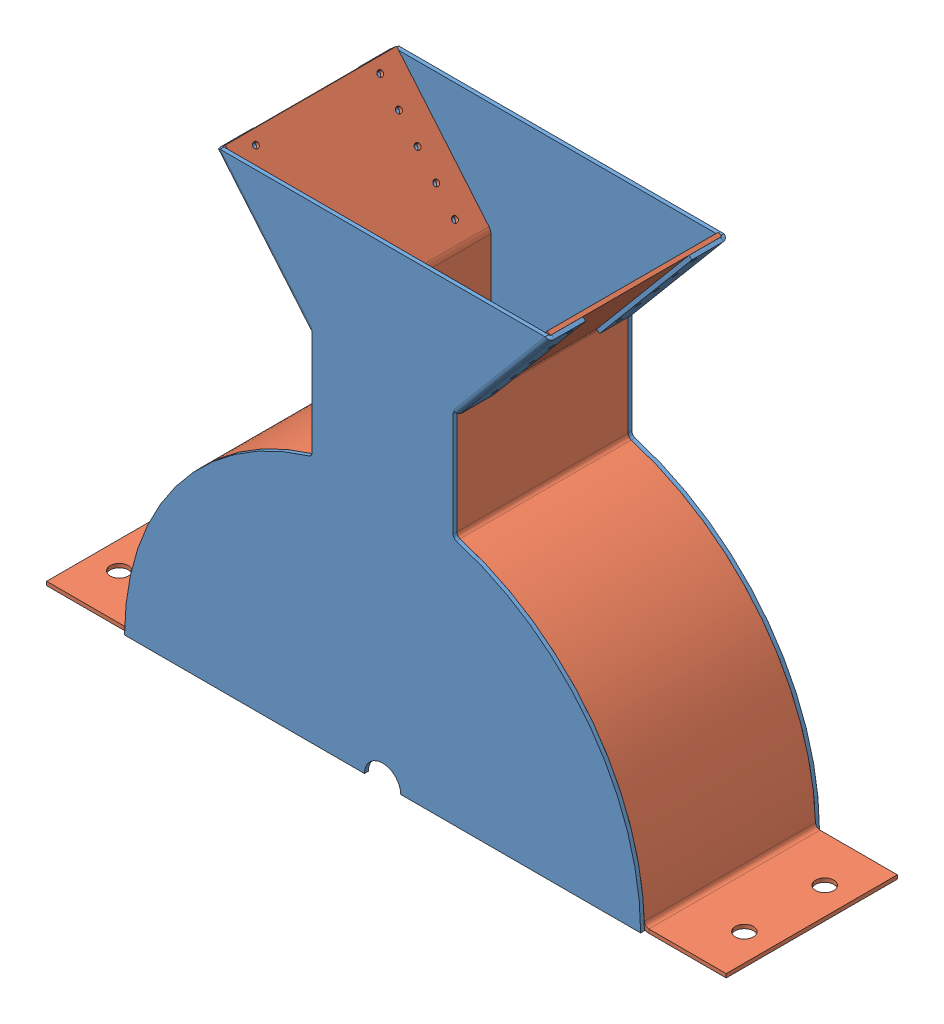
SolidWorks assembly Upper Assembly, configuration Default. Lengths in mm.
Overall size (475.23 329.37 125.4).
4 component instances, 2 part files, 7 mates.
Components (placement in the parent):
- Upper Assembly - Front Face-1: Upper Assembly - Front Face [Default] at (66.8996 -23.7984 322.0973) size (360.91 328.1 25.59)
- Upper Assembly - Front Face-2: Upper Assembly - Front Face [Default] at (66.8996 -23.7984 197.0861) x (-1 0 0) z (0 0 -1) size (360.91 328.1 25.59)
- Upper Assembly - Side Piece 2.0-1: Upper Assembly - Side Piece 2.0 [Default] at (66.8996 -23.7984 199.7429) x (1 -0.000027 0) z (0 0 1) size (190.98 329.36 119.7)
- Upper Assembly - Side Piece 2.0-2: Upper Assembly - Side Piece 2.0 [Default] at (66.8996 -23.7984 319.4404) x (-1 -0.000027 0) z (0 0 -1) size (190.98 329.36 119.7)
Mates (geometry in assembly coordinates):
- Concentric1: concentric aligned: circle of Upper Assembly - Front Face-1; circle of Upper Assembly - Side Piece 2.0-1
- Coincident16: coincident anti-aligned: plane of Upper Assembly - Front Face-1 through (66.8996 -23.7984 319.4404) normal (0 0 -1); plane of Upper Assembly - Side Piece 2.0-1 through (19.6484 227.7214 319.4404) normal (0 0 1)
- Parallel3: parallel anti-aligned: plane of Upper Assembly - Front Face-2 through (160.9741 55.1395 197.0861) normal (0.766044 0.642788 0); plane of Upper Assembly - Side Piece 2.0-1 through (160.9855 55.1491 199.7429) normal (-0.766044 -0.642788 0)
- Parallel4: parallel anti-aligned: plane of Upper Assembly - Front Face-1 through (160.9741 55.1395 322.0973) normal (0.766044 0.642788 0); plane of Upper Assembly - Side Piece 2.0-1 through (160.9855 55.1491 199.7429) normal (-0.766044 -0.642788 0)
- Coincident19: coincident anti-aligned: circle of Upper Assembly - Front Face-1; circle of Upper Assembly - Side Piece 2.0-2
- Parallel5: parallel anti-aligned: plane of Upper Assembly - Front Face-1 through (-27.1749 55.1395 322.0973) normal (-0.766044 0.642788 0); plane of Upper Assembly - Side Piece 2.0-2 through (-27.1863 55.1491 319.4404) normal (0.766044 -0.642788 0)
- Coincident21: coincident aligned: circle of Upper Assembly - Front Face-2; circle of Upper Assembly - Side Piece 2.0-2
